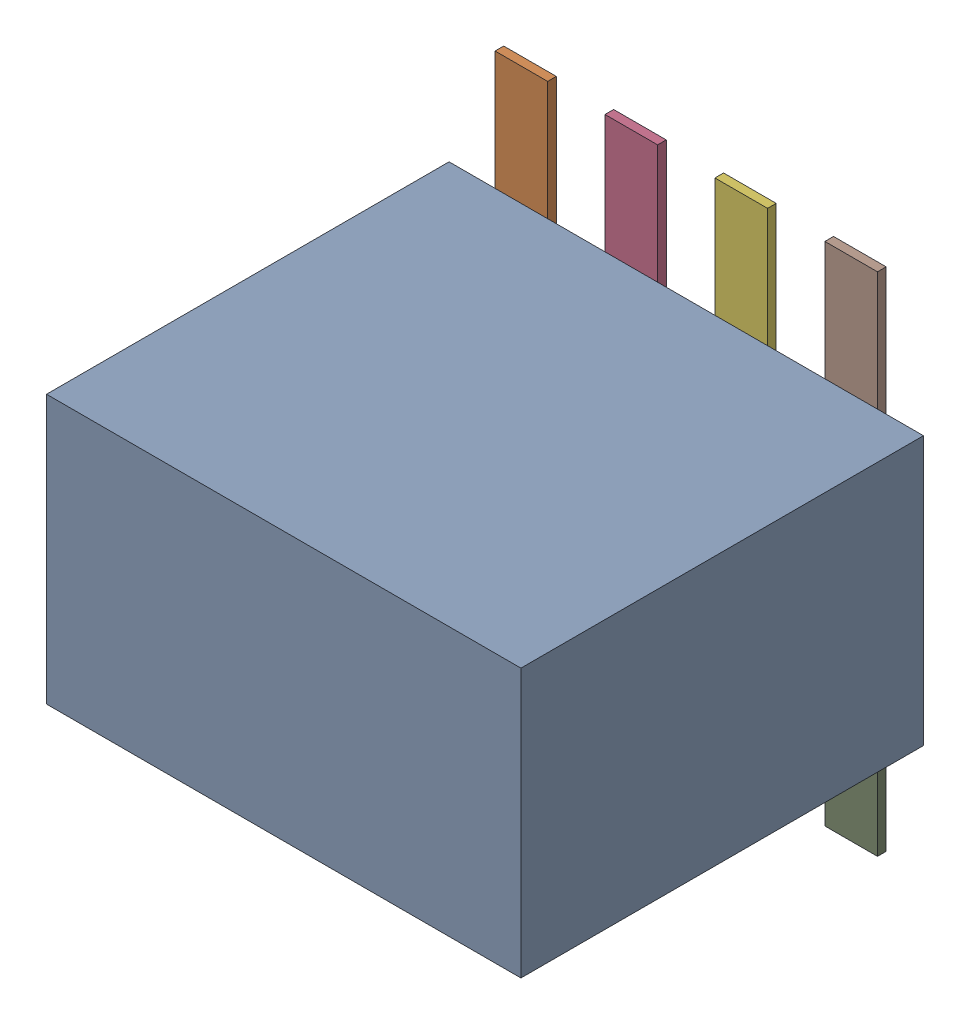
SolidWorks assembly 9452611696_1.step, configuration Default. Lengths in mm.
Overall size (5.48 5.85 4.75).
2 component instances, 2 part files, 0 mates.
Components (placement in the parent):
- Body_2.step-11: Body_2.step [Default] at (0 0 0.1) size (5.48 3.1 4.65)
- Pins_1.step-11: Pins_1.step [Default] at origin size (4.42 5.85 0.1)
